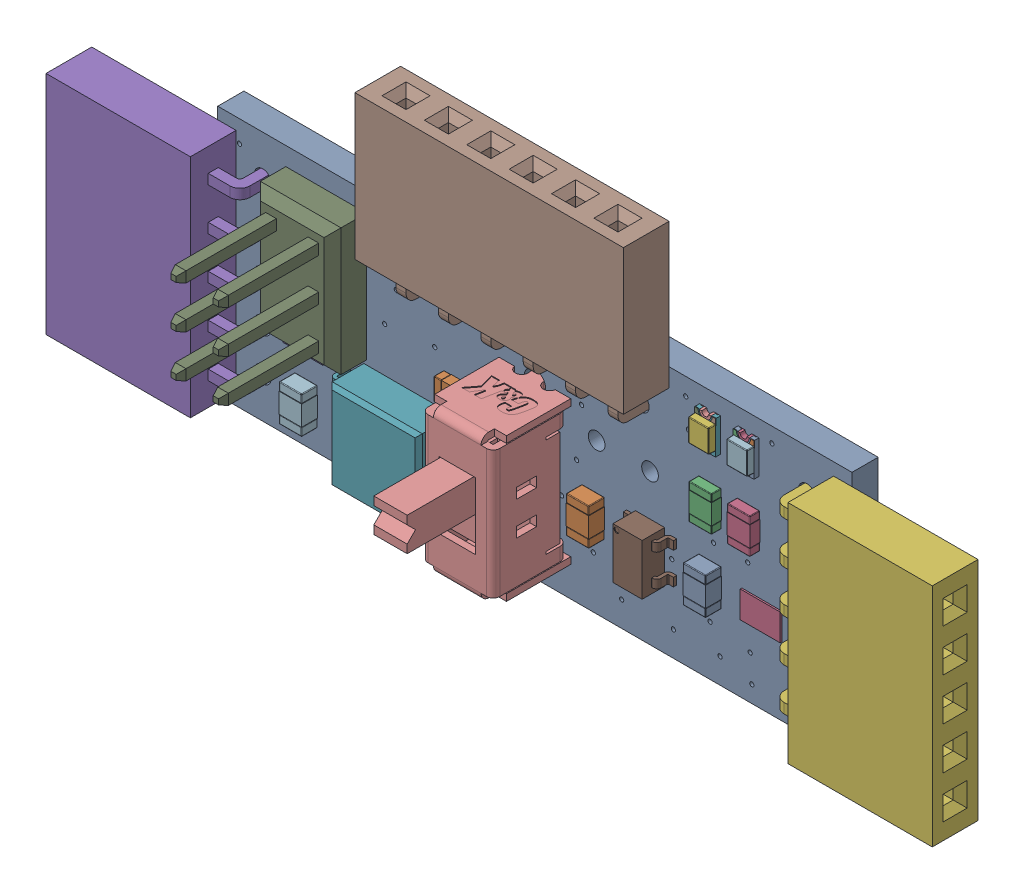
SolidWorks assembly PCB Component, configuration Default. Lengths in mm.
Overall size (53.1 22.55 11.8).
31 component instances, 16 part files, 0 mates.
Components (placement in the parent):
- Board-1: Board [Default] at origin size (38 15 1.57)
- 1K-1: 1K [Default] at (14.6 7.4 1.57) x (-1 0 0) z (0 0 1) size (2.11 1.36 0.61)
- 1K-2: 1K [Default] at (29.5 9.2 1.57) x (0 1 0) z (0 0 1) size (2.11 1.36 0.61)
- 1K-3: 1K [Default] at (31.8 9.2 1.57) x (0 1 0) z (0 0 1) size (2.11 1.36 0.61)
- GREEN-1: GREEN [Default] at (29.5 13 1.57) x (0 -1 0) z (0 0 1) size (2 1.25 0.7)
  - base-1: base [Default] at (0.8 0 0) x (-1 0 0) z (0 0 1) size (0.4 1 0.3)
  - cover-1: cover [Default] at (0 0 0.3) size (1.4 1.25 0.4)
  - housing-1: housing [Default] at origin size (2 1.25 0.3)
  - marking-1: marking [Default] at (-0.8 0.525 0.26) size (0.4 0.48 0.04)
  - marking-2: marking [Default] at (-0.8 -0.525 0.3) x (1 0 0) z (0 0 -1) size (0.4 0.48 0.04)
  - base_2-1: base_2 [Default] at (-0.8 0 0) size (0.4 1 0.3)
- GREEN-2: GREEN [Default] at (31.8 13 1.57) x (0 -1 0) z (0 0 1) size (2 1.25 0.7)
  - base-1: base [Default] at (0.8 0 0) x (-1 0 0) z (0 0 1) size (0.4 1 0.3)
  - cover-1: cover [Default] at (0 0 0.3) size (1.4 1.25 0.4)
  - housing-1: housing [Default] at origin size (2 1.25 0.3)
  - marking-1: marking [Default] at (-0.8 0.525 0.26) size (0.4 0.48 0.04)
  - marking-2: marking [Default] at (-0.8 -0.525 0.3) x (1 0 0) z (0 0 -1) size (0.4 0.48 0.04)
  - base_2-1: base_2 [Default] at (-0.8 0 0) size (0.4 1 0.3)
- Thumbstick-1: Thumbstick [Default] at (2.7 12.6 1.57) x (0 -1 0) z (0 0 1) size (13.55 10.55 5.89)
- Thumbstick-2: Thumbstick [Default] at (35.3 2.4 1.57) x (0 1 0) z (0 0 1) size (13.55 10.55 5.89)
- ATtiny85V-1: ATtiny85V [Default] at (11.5 3.4 1.57) x (-1 0 0) z (0 0 1) size (8.26 5.35 2.16)
- HM-10-1: HM-10 [Default] at (25.35 12.3 1.57) x (-1 0 0) z (0 0 1) size (16.09 10.55 5.89)
- PTH VERT MALE-1: PTH VERT MALE [Default] at (5.73 8.06 1.57) x (0 1 0) z (0 0 1) size (7.62 4.83 11.43)
- 300mA_30V-1: 300mA_30V [Default] at (19 6.1 1.57) size (4.3 8.6 11.5)
- MCP1802 300mA_3.3V-1: MCP1802 300mA_3.3V [Default] at (26 5.1 1.57) size (3 3.05 1.45)
- 1uF_25V-1: 1uF_25V [Default] at (5.3 2.4 1.57) x (0 1 0) z (0 0 1) size (2.21 1.36 0.96)
- 1uF_25V-2: 1uF_25V [Default] at (29.5 5.1 1.57) x (0 -1 0) z (0 0 1) size (2.21 1.36 0.96)
- 1uF_25V-3: 1uF_25V [Default] at (22.5 5.2 1.57) x (0 -1 0) z (0 0 1) size (2.21 1.36 0.96)
- BATTERY_LIPO_2S-1: BATTERY_LIPO_2S [Default] at (24.3 9 0) x (1 0 0) z (0 0 -1) size (6 3.45 0.1)
- JUMPER_SMD_3-PAD_NO_SILK-1: JUMPER_SMD_3-PAD_NO_SILK [Default] at (32.6 4.9 1.57) size (2.4 1.6 0.1)
- JUMPER_SMD_3-PAD_NO_SILK-2: JUMPER_SMD_3-PAD_NO_SILK [Default] at (5.2 5.6 1.57) size (2.4 1.6 0.1)
